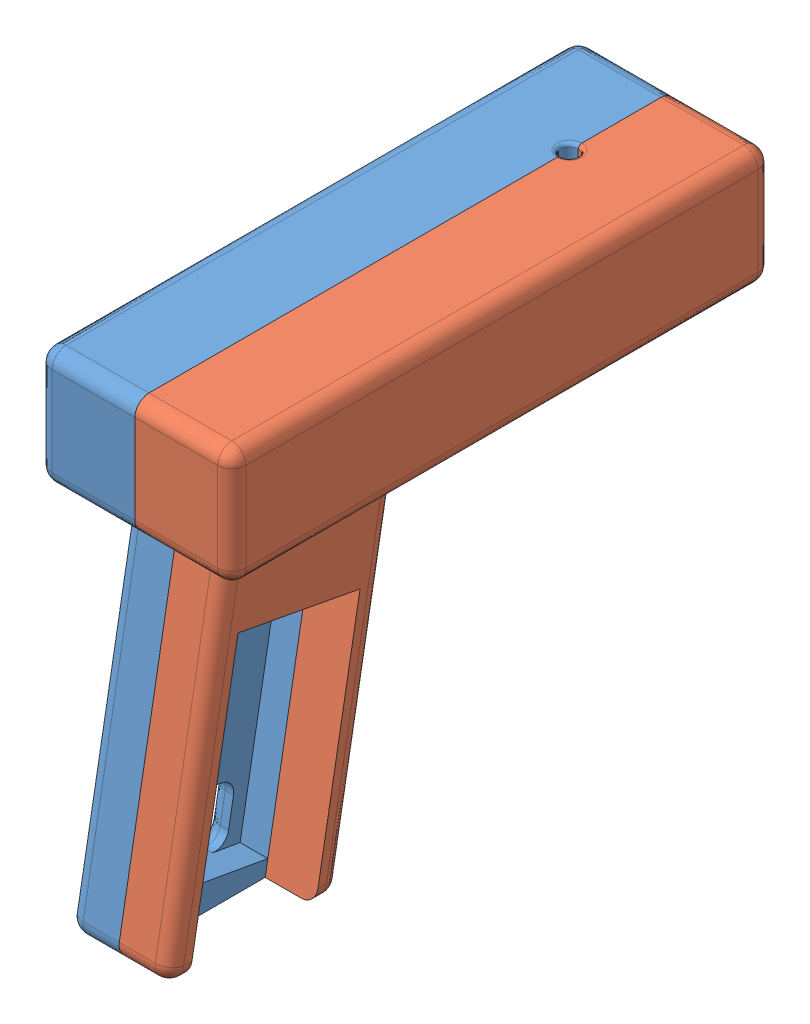
SolidWorks assembly BlasterAssembled, configuration Default. Lengths in mm.
Overall size (54.7 134.7 156.85).
2 component instances, 2 part files, 2 mates.
Components (placement in the parent):
- BlasterLeft-1: BlasterLeft [Default] at (177.3776 43.8817 40.4003) size (27.35 134.7 156.85)
- BlasterRight-1: BlasterRight [Default] at (204.7276 76.9817 40.4003) x (1 0 0) z (0 1 0) size (30.35 156.85 134.7)
Mates (geometry in assembly coordinates):
- Concentric2: concentric anti-aligned: circle of BlasterLeft-1; circle of BlasterRight-1
- Coincident1: coincident anti-aligned: circle of BlasterLeft-1; circle of BlasterRight-1
